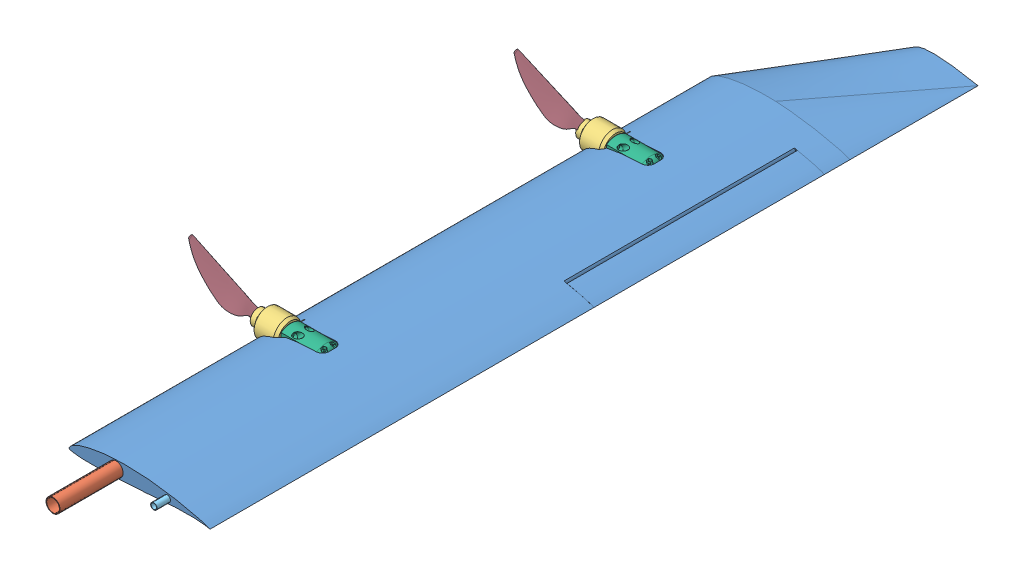
SolidWorks assembly wing assy, configuration Default. Lengths in mm.
Overall size (266.07 349.28 1298.5).
9 component instances, 6 part files, 20 mates.
Components (placement in the parent):
- half wing-1: half wing [Default] at (-143.7401 12.5498 -494.9574) size (220.41 30.82 1200)
- main wing spar-1: main wing spar [Default] at (-70.4068 20.7451 -496.4574) size (22 22 1100)
- Motor Tmotor mn3520-11 400kv-1: Motor Tmotor mn3520-11 400kv [Default] at (-115.4068 20.7451 -320.4574) x (-1 0 0) z (0 -1 0) size (74 48.5 43)
- Motor Tmotor mn3520-11 400kv-2: Motor Tmotor mn3520-11 400kv [Default] at (-115.4068 20.7451 188.0426) x (-1 0 0) z (0 -1 0) size (74 48.5 43)
- 15x5 prop-1: 15x5 prop [Default] at (-164.5593 20.7451 -320.4574) x (0 -0.571492 0.820608) z (0 -0.820608 -0.571492) size (52.83 14.05 386.3)
- 15x5 prop-2: 15x5 prop [Default] at (-166.4069 20.7451 188.0426) x (0 -0.561683 0.827353) z (0 -0.827353 -0.561683) size (52.83 14.05 386.3)
- secondary wing spar-2: secondary wing spar [Default] at (9.5932 20.7451 -493.9574) size (10 10 1020)
- Newmount1-1: Newmount1 [Default] at (-115.4068 20.7451 188.0426) x (0 0 -1) z (1 0 0) size (30 33.2 65.5)
- Newmount1-2: Newmount1 [Default] at (-115.4068 20.7451 -320.4574) x (0 0 -1) z (1 0 0) size (30 33.2 65.5)
Mates (geometry in assembly coordinates):
- Concentric1: concentric aligned: cylinder of half wing-1 through (-70.4068 20.7451 505.0426) axis (0 0 -1) radius 11; cylinder of main wing spar-1 through (-70.4068 20.7451 603.5426) axis (0 0 -1) radius 11
- Parallel1: parallel aligned: plane of Motor Tmotor mn3520-11 400kv-2 through (-115.4068 20.7451 188.0426) normal (1 0 0)
- Coincident4: coincident: line of main wing spar-1 through (-70.4068 20.7451 603.5426) axis (0 0 -1); plane of Motor Tmotor mn3520-11 400kv-2 through (-115.4068 20.7451 188.0426) normal (0 -1 0)
- Distance4: distance = 45 mm: plane of Motor Tmotor mn3520-11 400kv-2 through (-115.4068 20.7451 188.0426) normal (1 0 0); line of main wing spar-1 through (-70.4068 20.7451 603.5426) axis (0 0 -1)
- Parallel2: parallel aligned: plane of Motor Tmotor mn3520-11 400kv-1 through (-115.4068 20.7451 -320.4574) normal (1 0 0)
- Coincident9: coincident: line of main wing spar-1 through (-70.4068 20.7451 603.5426) axis (0 0 -1); plane of Motor Tmotor mn3520-11 400kv-1 through (-115.4068 20.7451 -320.4574) normal (0 -1 0)
- Distance5: distance = 45 mm: plane of Motor Tmotor mn3520-11 400kv-1 through (-115.4068 20.7451 -320.4574) normal (1 0 0); line of main wing spar-1 through (-70.4068 20.7451 603.5426) axis (0 0 -1)
- Concentric2: concentric anti-aligned: cylinder of Motor Tmotor mn3520-11 400kv-1 through (-115.4068 20.7451 -320.4574) axis (1 0 0) radius 4; cylinder of 15x5 prop-1 through (-153.0215 20.7451 -320.4574) axis (-1 0 0) radius 3
- Tangent4: tangent aligned: plane of Motor Tmotor mn3520-11 400kv-1 through (-165.4068 20.7451 -332.9574) normal (-1 0 0); face of 15x5 prop-1
- Concentric3: concentric anti-aligned: cylinder of Motor Tmotor mn3520-11 400kv-2 through (-115.4068 20.7451 188.0426) axis (1 0 0) radius 4; cylinder of 15x5 prop-2 through (-154.8692 20.7451 188.0426) axis (-1 0 0) radius 3
- Tangent6: tangent anti-aligned: plane of Motor Tmotor mn3520-11 400kv-2 through (-165.4068 20.7451 175.5426) normal (-1 0 0); edge_curve of 15x5 prop-2
- Distance7: distance = 98.5 mm aligned: plane of half wing-1 through (-142.4175 15.0963 505.0426) normal (0 0 1); plane of main wing spar-1 through (-70.4068 20.7451 603.5426) normal (0 0 1)
- Concentric4: concentric anti-aligned: cylinder of half wing-1 through (9.5932 20.7451 -494.9574) axis (0 0 1) radius 5; cylinder of secondary wing spar-2 through (9.5932 20.7451 526.0426) axis (0 0 -1) radius 5
- Distance8: distance = 21 mm aligned: plane of secondary wing spar-2 through (9.5932 20.7451 526.0426) normal (0 0 1); plane of half wing-1 through (-142.4175 15.0963 505.0426) normal (0 0 1)
- Coincident10: coincident anti-aligned: line of main wing spar-1 through (-70.4068 20.7451 603.5426) axis (0 0 -1); line of Newmount1-1 through (-70.4068 20.7451 173.0426) axis (0 0 1)
- Concentric5: concentric anti-aligned: line of Motor Tmotor mn3520-11 400kv-2 through (-189.4068 20.7451 188.0426) axis (1 0 0); cylinder of Newmount1-1 through (-95.4068 20.7451 188.0426) axis (-1 0 0) radius 5
- Coincident12: coincident anti-aligned: line of half wing-1 through (-70.4068 20.7451 505.0426) axis (0 0 -1); line of Newmount1-2 through (-70.4068 20.7451 -335.4574) axis (0 0 1)
- Concentric7: concentric anti-aligned: line of Motor Tmotor mn3520-11 400kv-1 through (-189.4068 20.7451 -320.4574) axis (1 0 0); cylinder of Newmount1-2 through (-95.4068 20.7451 -320.4574) axis (-1 0 0) radius 5
- Distance10: distance = 825.5 mm: line of Motor Tmotor mn3520-11 400kv-1 through (-150.4068 20.7451 -320.4574) axis (1 0 0); plane of half wing-1 through (-142.4175 15.0963 505.0426) normal (0 0 1)
- Distance11: distance = 317 mm: line of Motor Tmotor mn3520-11 400kv-2 through (-150.4068 20.7451 188.0426) axis (1 0 0); plane of half wing-1 through (-142.4175 15.0963 505.0426) normal (0 0 1)
